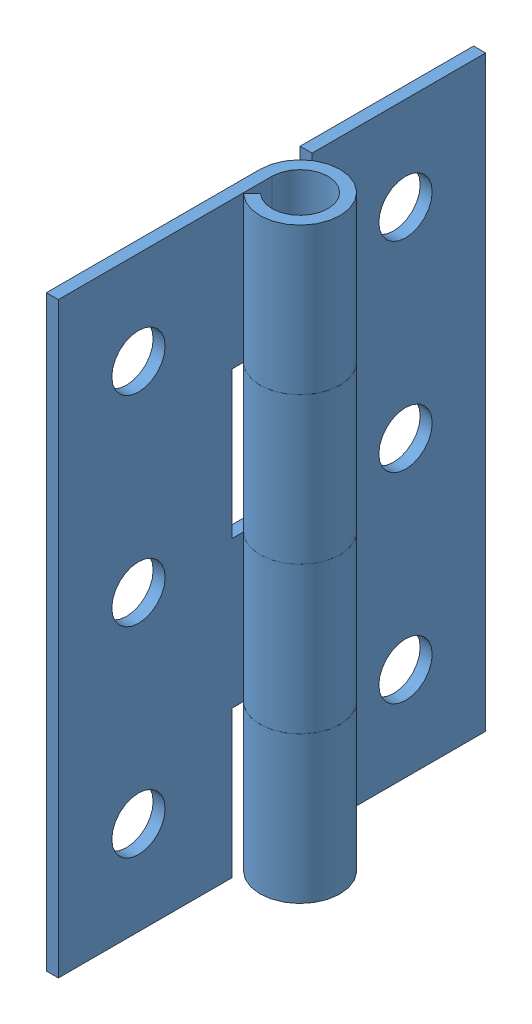
SolidWorks assembly HingeFull, configuration Default. Lengths in mm.
Overall size (6 44 32).
2 component instances, 1 part files, 1 mates.
Components (placement in the parent):
- HingePart-7: HingePart [Default] at (-40.0421 -47.6115 14.8207) size (6 44 19)
- HingePart-8: HingePart [Default] at (-40.0421 -3.6115 -17.1793) x (1 0 0) z (0 0 -1) size (6 44 19)
Mates (geometry in assembly coordinates):
- Hinge8: hinge = 0 rad anti-aligned: cylinder of HingePart-8 through (-37.0421 -47.6115 -1.1793) axis (0 1 0) radius 2.1; cylinder of HingePart-8 through (-37.0421 -3.6115 -1.1793) axis (0 -1 0) radius 2.1; plane of HingePart-7 through (86.9579 -14.6115 1.8207) normal (0 1 0); plane of HingePart-7 through (86.9579 -14.6115 -4.1793) normal (0 -1 0); unknown of HingePart-8; plane of HingePart-7 through (-39.1421 -47.6115 14.8207) normal (1 0 0)
